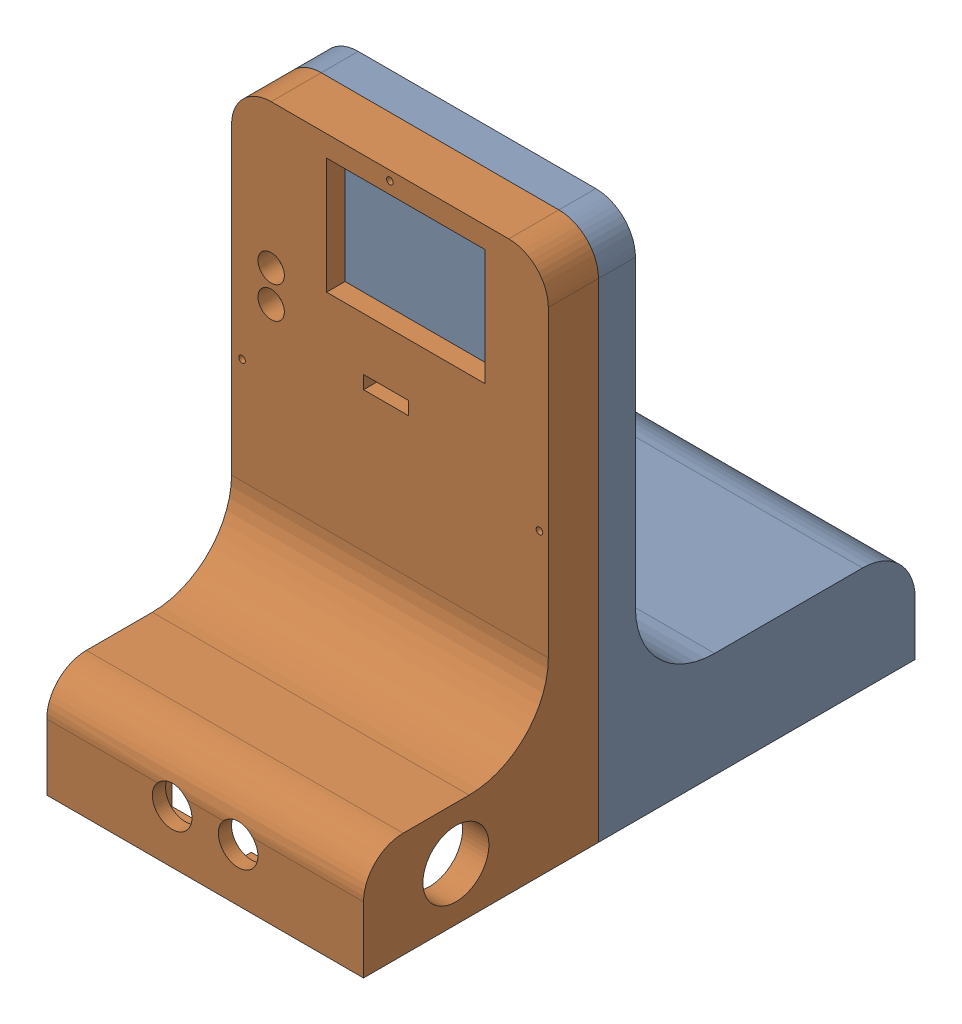
SolidWorks assembly Assemblage_projet, configuration Défaut. Lengths in mm.
Overall size (120 200 209).
2 component instances, 2 part files, 3 mates.
Components (placement in the parent):
- Pièce Maquette Back DEEP-1: Pièce Maquette Back DEEP [Défaut] at (-22.1011 -103.2146 76.6949) size (120 200 120)
- Pièce Maquette Front DEEP-1: Pièce Maquette Front DEEP [Défaut] at (-22.1011 -103.2146 54.6949) size (120 200 89)
Mates (geometry in assembly coordinates):
- Coïncidente1: coincident: plane of Pièce Maquette Back DEEP-1 through (97.8989 96.7854 65.6949) normal (0 0 1); plane of Pièce Maquette Front DEEP-1 through (97.8989 96.108 65.6949) normal (0 0 -1)
- Coïncidente2: coincident: line of Pièce Maquette Back DEEP-1 through (97.8989 -103.2146 65.6949) axis (0 1 0); line of Pièce Maquette Front DEEP-1 through (97.8989 81.108 65.6949) axis (0 -1 0)
- Coïncidente3: coincident aligned: line of Pièce Maquette Back DEEP-1 through (82.8989 96.7854 65.6949) axis (-1 0 0); line of Pièce Maquette Front DEEP-1 through (82.8989 96.7854 65.6949) axis (-1 0 0)
